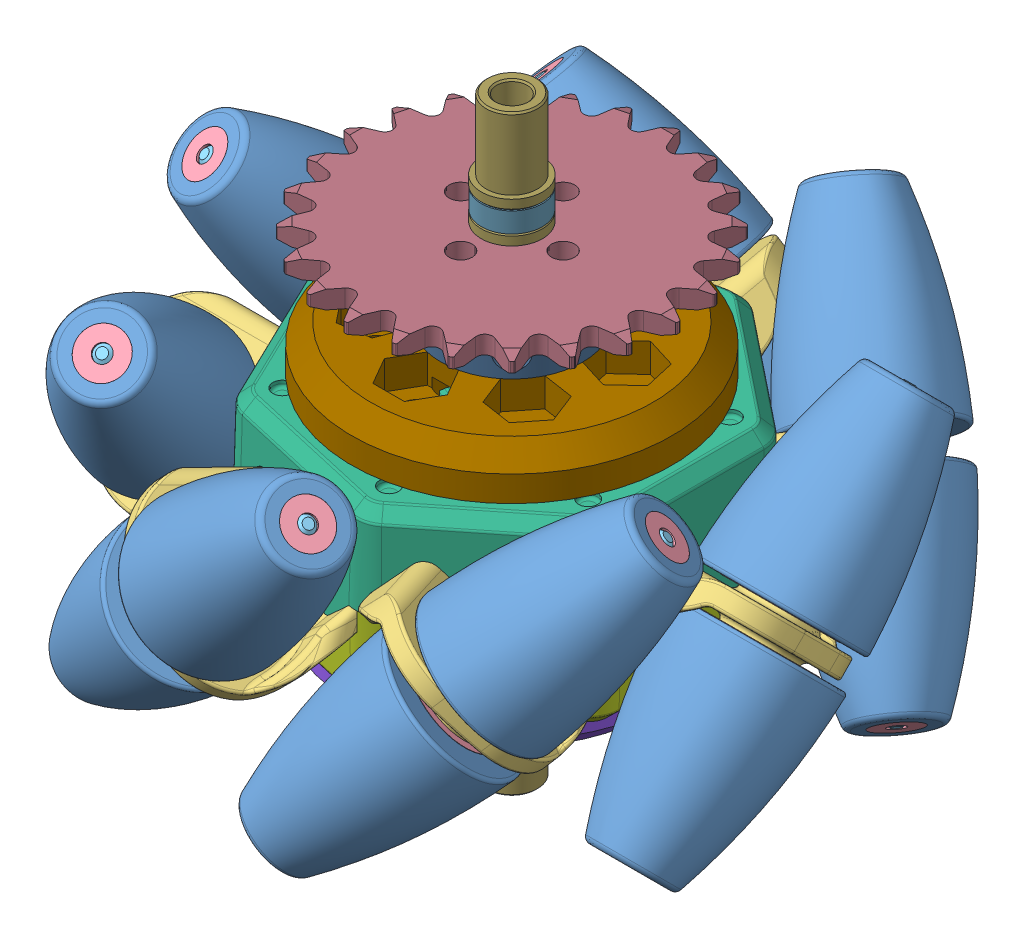
SolidWorks assembly Mecanum Left Assembly, configuration Default. Lengths in mm.
Overall size (116.24 92.45 118.47).
72 component instances, 14 part files, 18 mates.
Components (placement in the parent):
- Mecanum Left-1: Mecanum Left [Default] at (35.1717 68.1525 91.4485) size (116.24 62.26 118.47)
  - Roller-1: Roller [Default] at (-8.8714 -0.1061 -39.3041) x (-0.709843 -0.615883 -0.341777) z (0.144671 0.347402 -0.926489) size (22.31 28.6 22.31)
  - Washer-1: Washer [Default] at (-2.1949 -6.9473 -40.8283) x (-0.689398 -0.707107 0.15726) z (0.68937 -0.707107 -0.15738) size (6 6 6.25)
  - Bracket Left-1: Bracket Left [Default] at origin size (28.34 25.51 28.03)
  - Roller Hub-2: Roller Hub [Default] at (25.0439 -0.1061 31.5645) x (0.446415 -0.698084 -0.559815) z (0.703674 -0.112601 0.701544) size (15.2 28.65 15.2)
  - Pin-1: Pin [Default] at (40.2927 0.0354 -0.0424) x (0.491193 -0.615883 -0.615969) z (0.871051 0.347402 0.34725) size (2.6 61.8 2.6)
  - Roller-3: Roller [Default] at (-36.2516 0.1061 17.5878) x (-0.306866 0.707107 -0.637051) z (-0.900888 0.000087 0.434052) size (22.31 28.6 22.31)
  - Washer-2: Washer [Default] at (19.6895 6.9473 -35.8342) x (-0.552772 -0.707107 -0.440957) z (0.552849 -0.707107 0.44086) size (6 6 6.25)
  - Roller-5: Roller [Default] at (25.1987 -0.1061 -31.441) x (-0.175349 -0.615883 -0.768076) z (0.814571 0.347402 -0.464528) size (22.31 28.6 22.31)
  - Washer-5: Washer [Default] at (-33.2899 -6.9473 -23.7392) x (-0.306866 -0.707107 0.637051) z (0.306754 -0.707107 -0.637104) size (6 6 6.25)
  - Bracket Left-2: Bracket Left [Default] x (0.62347 0 -0.781847) z (0.781847 0 0.62347) size (28.34 25.51 28.03)
  - Pin-2: Pin [Default] at (25.1544 0.0354 31.4763) x (0.787838 -0.615883 0) z (0.271578 0.347402 0.897528) size (2.6 61.8 2.6)
  - Roller-6: Roller [Default] at (-36.3528 0.1061 -17.3777) x (0.306754 0.707107 -0.637104) z (-0.901039 0.000087 -0.433738) size (22.31 28.6 22.31)
  - Washer-6: Washer [Default] at (-15.741 6.9473 -37.7357) x (-0.689398 -0.707107 0.15726) z (0.68937 -0.707107 -0.15738) size (6 6 6.25)
  - Roller-9: Roller [Default] at (40.2927 -0.1061 0.099) x (0.491193 -0.615883 -0.615969) z (0.871051 0.347402 0.34725) size (22.31 28.6 22.31)
  - Washer-8: Washer [Default] at (-39.3157 -6.9473 11.2269) x (0.306754 -0.707107 0.637104) z (-0.306866 -0.707107 -0.637051) size (6 6 6.25)
  - Bracket Left-3: Bracket Left [Default] x (-0.22257 0 -0.974917) z (0.974917 0 -0.22257) size (28.34 25.51 28.03)
  - Bracket Left-4: Bracket Left [Default] x (-0.901001 0 -0.433816) z (0.433816 0 -0.901001) size (28.34 25.51 28.03)
  - Roller Hub-6: Roller Hub [Default] at (-36.2516 0.1061 17.5878) x (-0.446512 0.698084 -0.559737) z (-0.840471 -0.112601 0.530028) size (15.2 28.65 15.2)
  - Roller-10: Roller [Default] at (-9.0782 0.1061 -39.2568) x (0.68937 0.707107 -0.15738) z (-0.222655 0.000087 -0.974897) size (22.31 28.6 22.31)
  - Washer-10: Washer [Default] at (-39.3176 6.9473 -11.2201) x (-0.306866 -0.707107 0.637051) z (0.306754 -0.707107 -0.637104) size (6 6 6.25)
  - Roller-13: Roller [Default] at (25.0439 -0.1061 31.5645) x (0.787838 -0.615883 0) z (0.271578 0.347402 0.897528) size (22.31 28.6 22.31)
  - Washer-11: Washer [Default] at (-15.7344 -6.9473 37.7385) x (0.68937 -0.707107 0.15738) z (-0.689398 -0.707107 -0.15726) size (6 6 6.25)
  - Bracket Left-5: Bracket Left [Default] x (-0.900926 0 0.433974) z (-0.433974 0 -0.900926) size (28.34 25.51 28.03)
  - Roller Hub-8: Roller Hub [Default] at (-36.3437 -0.1061 17.3967) x (0.446512 -0.698084 0.559737) z (-0.840471 -0.112601 0.530028) size (15.2 28.65 15.2)
  - Roller-14: Roller [Default] at (25.0329 0.1061 -31.5732) x (0.552849 0.707107 0.44086) z (0.623402 0.000087 -0.781901) size (22.31 28.6 22.31)
  - Washer-14: Washer [Default] at (-33.2858 6.9473 23.745) x (0.306754 -0.707107 0.637104) z (-0.306866 -0.707107 -0.637051) size (6 6 6.25)
  - Roller Hub-11: Roller Hub [Default] at (25.1987 -0.1061 -31.441) x (-0.645131 -0.698084 -0.310619) z (0.527331 -0.112601 -0.842166) size (15.2 28.65 15.2)
  - Roller Hub-12: Roller Hub [Default] at (25.0329 0.1061 -31.5732) x (0.645131 0.698084 0.310619) z (0.527331 -0.112601 -0.842166) size (15.2 28.65 15.2)
  - Pin-5: Pin [Default] at (-8.9197 0.0354 39.293) x (0.491301 -0.615883 0.615883) z (-0.532275 0.347402 0.772007) size (2.6 61.8 2.6)
  - Washer-15: Washer [Default] at (19.6958 -6.9473 35.8307) x (0.552849 -0.707107 -0.44086) z (-0.552772 -0.707107 0.440957) size (6 6 6.25)
  - Bracket Left-6: Bracket Left [Default] x (-0.222399 0 0.974956) z (-0.974956 0 -0.222399) size (28.34 25.51 28.03)
  - Roller Hub-13: Roller Hub [Default] at (40.2927 -0.1061 0.099) x (-0.159363 -0.698084 -0.698056) z (0.98722 -0.112601 -0.112773) size (15.2 28.65 15.2)
  - Roller Hub-14: Roller Hub [Default] at (-36.3528 0.1061 -17.3777) x (0.159242 0.698084 -0.698084) z (-0.938409 -0.112601 -0.326663) size (15.2 28.65 15.2)
  - Roller-17: Roller [Default] at (40.2927 0.1061 -0.1131) x (0 0.707107 0.707107) z (1 0.000087 -0.000087) size (22.31 28.6 22.31)
  - Washer-17: Washer [Default] at (-2.1877 6.9473 40.8287) x (0.68937 -0.707107 0.15738) z (-0.689398 -0.707107 -0.15726) size (6 6 6.25)
  - Roller Hub-17: Roller Hub [Default] at (40.2927 0.1061 -0.1131) x (0.159363 0.698084 0.698056) z (0.98722 -0.112601 -0.112773) size (15.2 28.65 15.2)
  - Pin-7: Pin [Default] at (-36.2823 0.0354 17.5241) x (-0.175215 -0.615883 0.768107) z (-0.935449 0.347402 0.065166) size (2.6 61.8 2.6)
  - Washer-19: Washer [Default] at (40.2939 -6.9473 6.9403) x (0 -0.707107 -0.707107) z (0.000123 -0.707107 0.707107) size (6 6 6.25)
  - Bracket Left-7: Bracket Left [Default] x (0.623607 0 0.781738) z (-0.781738 0 0.623607) size (28.34 25.51 28.03)
  - Roller Hub-18: Roller Hub [Default] at (-36.2608 -0.1061 -17.5689) x (-0.159242 -0.698084 0.698084) z (-0.938409 -0.112601 -0.326663) size (15.2 28.65 15.2)
  - Roller-20: Roller [Default] at (-9.0576 -0.1061 39.2616) x (0.491301 -0.615883 0.615883) z (-0.532275 0.347402 0.772007) size (22.31 28.6 22.31)
  - Washer-20: Washer [Default] at (30.5578 6.9473 27.1659) x (0.552849 -0.707107 -0.44086) z (-0.552772 -0.707107 0.440957) size (6 6 6.25)
  - Pin-9: Pin [Default] at (-36.3221 0.0354 -17.4414) x (-0.709783 -0.615883 0.341901) z (-0.634175 0.347402 -0.690749) size (2.6 61.8 2.6)
  - Hub Inner Left-1: Hub Inner Left [Default] at origin size (62.26 19.81 61.13)
  - Roller Hub-21: Roller Hub [Default] at (-9.0645 -0.1061 39.26) x (0.716016 -0.698084 0) z (-0.109781 -0.112601 0.987557) size (15.2 28.65 15.2)
  - Roller Hub-22: Roller Hub [Default] at (-8.8577 0.1061 39.3072) x (-0.716016 0.698084 0) z (-0.109781 -0.112601 0.987557) size (15.2 28.65 15.2)
  - Roller Hub-23: Roller Hub [Default] at (-9.0782 0.1061 -39.2568) x (0.645077 0.698084 -0.310732) z (-0.329669 -0.112601 -0.937358) size (15.2 28.65 15.2)
  - Roller-22: Roller [Default] at (-36.3437 -0.1061 17.3967) x (-0.175215 -0.615883 0.768107) z (-0.935449 0.347402 0.065166) size (22.31 28.6 22.31)
  - Washer-23: Washer [Default] at (40.2915 6.9473 -6.9544) x (0 -0.707107 -0.707107) z (0.000123 -0.707107 0.707107) size (6 6 6.25)
  - Roller Hub-24: Roller Hub [Default] at (25.2097 0.1061 31.4322) x (-0.446415 0.698084 0.559815) z (0.703674 -0.112601 0.701544) size (15.2 28.65 15.2)
  - Pin-11: Pin [Default] at (-9.0092 0.0354 -39.2726) x (-0.709843 -0.615883 -0.341777) z (0.144671 0.347402 -0.926489) size (2.6 61.8 2.6)
  - Roller-24: Roller [Default] at (25.2152 0.1061 31.4278) x (-0.552772 0.707107 0.440957) z (0.623675 0.000087 0.781684) size (22.31 28.6 22.31)
  - Roller Hub-27: Roller Hub [Default] at (-8.8714 -0.1061 -39.3041) x (-0.645077 -0.698084 0.310732) z (-0.329669 -0.112601 -0.937358) size (15.2 28.65 15.2)
  - Roller-25: Roller [Default] at (-36.2608 -0.1061 -17.5689) x (-0.709783 -0.615883 0.341901) z (-0.634175 0.347402 -0.690749) size (22.31 28.6 22.31)
  - Washer-26: Washer [Default] at (30.553 -6.9473 -27.1713) x (-0.552772 -0.707107 -0.440957) z (0.552849 -0.707107 0.44086) size (6 6 6.25)
  - Hub Outer Left-1: Hub Outer Left [Default] at origin size (61.9 23.71 60.76)
  - Pin-13: Pin [Default] at (25.0881 0.0354 -31.5291) x (-0.175349 -0.615883 -0.768076) z (0.814571 0.347402 -0.464528) size (2.6 61.8 2.6)
  - Roller-28: Roller [Default] at (-8.8508 0.1061 39.3087) x (-0.689398 0.707107 -0.15726) z (-0.222314 0.000087 0.974975) size (22.31 28.6 22.31)
- Mecanum Hub A-1: Mecanum Hub A [Default] at (35.1717 56.1525 91.4485) x (1 0 0) z (0 -1 0) size (50 50 12)
- Mecanum Hub B-1: Mecanum Hub B [Default] at (35.1717 80.1525 91.4485) x (1 0 0) z (0 -1 0) size (50 50 12)
- Tetrix Axle Hub-1: Tetrix Axle Hub [Default] at (35.1717 89.1525 91.4485) x (1 0 0) z (0 -1 0) size (22.1 22.1 9.5)
  - Tetrix Axle Hub Body-1: Tetrix Axle Hub Body [Default] at origin size (22.1 22.1 9.5)
  - Tetrix Axle Hub Set Screw-1: Tetrix Axle Hub Set Screw [Default] at (6.9308 6.9308 -3.325) x (-0.707107 0.707107 0) z (0 0 1) size (4.83 7.94 4.83)
- Tetrix Axle Hub-2: Tetrix Axle Hub [Default] at (35.1717 47.1525 91.4485) x (1 0 0) z (0 1 0) size (22.1 22.1 9.5)
  - Tetrix Axle Hub Body-1: Tetrix Axle Hub Body [Default] at origin size (22.1 22.1 9.5)
  - Tetrix Axle Hub Set Screw-1: Tetrix Axle Hub Set Screw [Default] at (6.9308 6.9308 -3.325) x (-0.707107 0.707107 0) z (0 0 1) size (4.83 7.94 4.83)
- Tetrix Bushing Bronze-1: Tetrix Bushing Bronze [Default] at (35.1717 40.4025 91.4485) x (-0.837169 0 -0.546944) z (-0.546944 0 0.837169) size (9.56 12.71 9.56)
- Tetrix Bushing Bronze-2: Tetrix Bushing Bronze [Default] at (35.1717 104.3025 91.4485) x (-0.837169 0 -0.546944) z (-0.546944 0 0.837169) size (9.56 12.71 9.56)
- Tetrix Bushing Bronze-3: Tetrix Bushing Bronze [Default] at (35.1717 107.4275 91.4485) x (0.996434 0 -0.084371) z (0.084371 0 0.996434) size (9.56 12.71 9.56)
- Tetrix Sprocket 24T-1: Tetrix Sprocket 24T [Default] at (35.1717 99.9025 91.4485) x (1 0 0) z (0 -1 0) size (52 52 6.8)
- Tetrix Axle Spacer Small-1: Tetrix Axle Spacer Small [Default] at (35.1717 105.865 91.4485) x (1 0 0) z (0 -1 0) size (9.5 9.5 3.12)
Mates (geometry in assembly coordinates):
- Coincident1: coincident anti-aligned: plane of Mecanum Left-1/Hub Inner Left-1 through (35.1717 82.1525 91.4485) normal (0 1 0); plane of Mecanum Hub B-1 through (60.1717 82.1525 91.4485) normal (0 -1 0)
- Concentric1: concentric anti-aligned: cylinder of Mecanum Left-1/Hub Inner Left-1 through (35.1717 82.1525 91.4485) axis (0 -1 0) radius 6; cylinder of Mecanum Hub B-1 through (35.1717 77.1525 91.4485) axis (0 1 0) radius 4.1
- Coincident2: coincident anti-aligned: plane of Mecanum Left-1/Hub Outer Left-1 through (35.1717 54.1525 91.4485) normal (0 -1 0); plane of Mecanum Hub A-1 through (60.1717 54.1525 91.4485) normal (0 1 0)
- Concentric2: concentric aligned: cylinder of Mecanum Left-1/Hub Outer Left-1 through (35.1717 54.1525 91.4485) axis (0 -1 0) radius 6; cylinder of Mecanum Hub A-1 through (35.1717 59.1525 91.4485) axis (0 -1 0) radius 4.1
- Coincident3: coincident anti-aligned: plane of Mecanum Hub B-1 through (35.1717 89.1525 91.4485) normal (0 1 0); plane of Tetrix Axle Hub-1/Tetrix Axle Hub Body-1 through (35.1717 89.1525 91.4485) normal (0 -1 0)
- Concentric3: concentric aligned: cylinder of Mecanum Hub B-1 through (35.1717 77.1525 91.4485) axis (0 1 0) radius 4.1; cylinder of Tetrix Axle Hub-1/Tetrix Axle Hub Body-1 through (35.1717 86.4025 91.4485) axis (0 1 0) radius 2.4375
- Coincident4: coincident anti-aligned: plane of Mecanum Hub A-1 through (35.1717 47.1525 91.4485) normal (0 -1 0); plane of Tetrix Axle Hub-2/Tetrix Axle Hub Body-1 through (35.1717 47.1525 91.4485) normal (0 1 0)
- Concentric4: concentric anti-aligned: cylinder of Mecanum Hub A-1 through (35.1717 59.1525 91.4485) axis (0 -1 0) radius 4.1; cylinder of Tetrix Axle Hub-2/Tetrix Axle Hub Body-1 through (35.1717 47.1525 91.4485) axis (0 1 0) radius 11.05
- Coincident5: coincident anti-aligned: plane of Tetrix Axle Hub-2/Tetrix Axle Hub Body-1 through (35.1717 40.4025 91.4485) normal (0 -1 0); plane of Tetrix Bushing Bronze-1 through (39.1733 40.4025 94.0629) normal (0 1 0)
- Concentric5: concentric aligned: cylinder of Tetrix Axle Hub-2/Tetrix Axle Hub Body-1 through (35.1717 47.1525 91.4485) axis (0 1 0) radius 11.05; cylinder of Tetrix Bushing Bronze-1 through (35.1717 40.4025 91.4485) axis (0 1 0) radius 4
- Concentric9: concentric anti-aligned: cylinder of Tetrix Bushing Bronze-2 through (35.1717 104.3025 91.4485) axis (0 1 0) radius 2.375; cylinder of Tetrix Bushing Bronze-3 through (35.1717 127.3678 91.4485) axis (0 -1 0) radius 4
- Coincident10: coincident anti-aligned: plane of Tetrix Axle Hub-1/Tetrix Axle Hub Body-1 through (35.1717 95.9025 91.4485) normal (0 1 0); plane of Tetrix Sprocket 24T-1 through (35.1717 95.9025 91.4485) normal (0 -1 0)
- Concentric10: concentric aligned: cylinder of Tetrix Axle Hub-1/Tetrix Axle Hub Body-1 through (35.1717 89.1525 91.4485) axis (0 -1 0) radius 11.05; cylinder of Tetrix Sprocket 24T-1 through (35.1717 102.7025 91.4485) axis (0 -1 0) radius 4
- Coincident11: coincident anti-aligned: plane of Tetrix Bushing Bronze-2 through (38.5204 102.7025 93.6363) normal (0 -1 0); plane of Tetrix Sprocket 24T-1 through (35.1717 102.7025 115.7735) normal (0 1 0)
- Concentric11: concentric anti-aligned: cylinder of Tetrix Bushing Bronze-2 through (35.1717 104.3025 91.4485) axis (0 1 0) radius 4; cylinder of Tetrix Sprocket 24T-1 through (35.1717 102.7025 91.4485) axis (0 -1 0) radius 4
- Concentric12: concentric anti-aligned: cylinder of Tetrix Bushing Bronze-2 through (35.1717 104.3025 91.4485) axis (0 1 0) radius 2.375; cylinder of Tetrix Axle Spacer Small-1 through (35.1717 107.4275 91.4485) axis (0 -1 0) radius 2.5
- Coincident12: coincident aligned: plane of Tetrix Bushing Bronze-2 through (39.1733 104.3025 94.0629) normal (0 1 0); circle of Tetrix Axle Spacer Small-1
- Coincident13: coincident anti-aligned: plane of Tetrix Bushing Bronze-3 through (30.4087 107.4275 91.8518) normal (0 -1 0); plane of Tetrix Axle Spacer Small-1 through (35.1717 107.4275 91.4485) normal (0 1 0)
